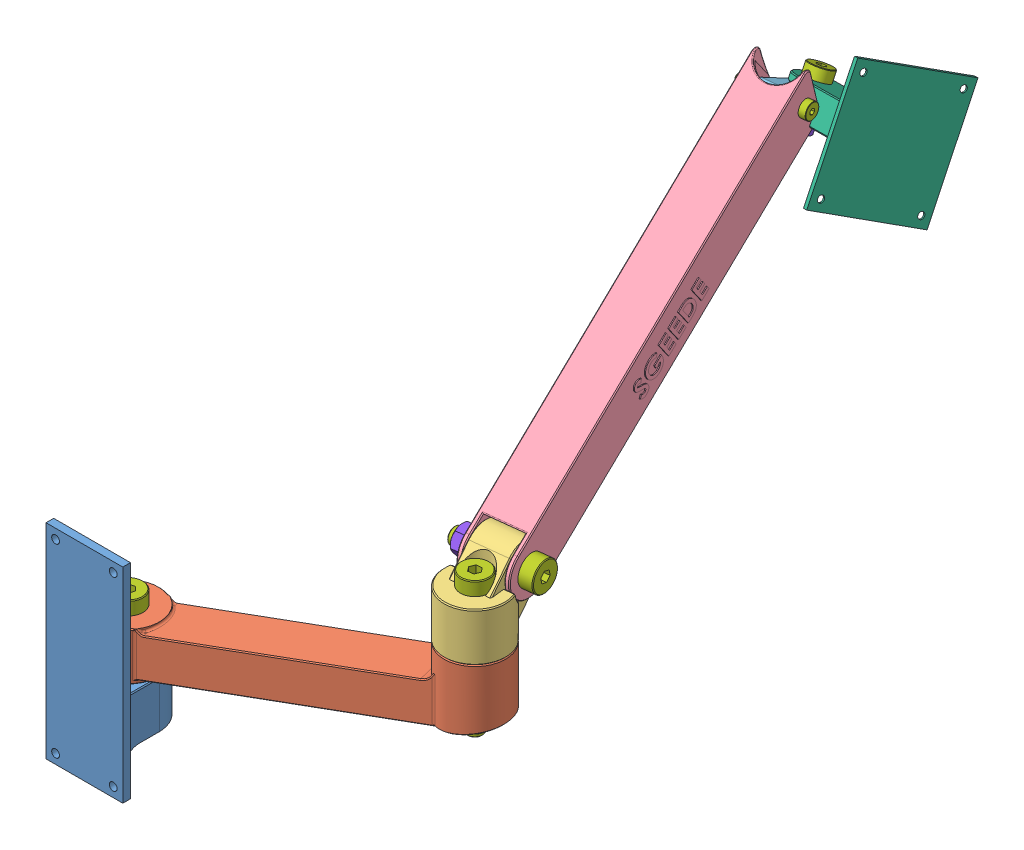
SolidWorks assembly lxhdstswall, configuration Default. Lengths in mm.
Overall size (397.37 577.27 596.46).
16 component instances, 8 part files, 31 mates.
Components (placement in the parent):
- WallBracket-1: WallBracket [Default] at (55.0507 127.7439 194.1309) size (80 213 78)
- Arm1-1: Arm1 [Default] at (29.5401 107.7439 138.7864) x (0.969584 0 -0.244757) z (0.244757 0 0.969584) size (361.03 125 64.03)
- Joint1-1: Joint1 [Default] at (343.0173 232.7439 85.438) x (-0.114521 0 -0.993421) z (0.993421 0 -0.114521) size (91.45 80.35 64)
- Arm2-1: Arm2 [Default] at (320.4593 406.352 -110.2427) x (-0.092601 0.588372 -0.803271) z (0.993421 0 -0.114521) size (449.82 50 51)
- Joint2-1: Joint2 [Default] at (299.6064 504.5489 -291.1318) x (-0.098971 -0.503119 -0.858531) z (0.993421 0 -0.114521) size (69 15 40)
- VesaMount-1: VesaMount [Default] at (397.6532 517.7237 -294.6599) x (-0.188445 0.482226 0.855539) z (-0.980392 -0.143481 -0.135072) size (120 120 121)
- socket head shoulder screw2_am-1: socket head shoulder screw2_am [B18.3.3M - 20 x 100 SHSS --N] at (55.0507 171.7439 158.1309) x (0 -1 0) z (0.270714 0 0.96266) size (136.4 30 30)
- socket head shoulder screw2_am-2: socket head shoulder screw2_am [B18.3.3M - 20 x 110 SHSS --N] at (343.0173 296.7439 85.438) x (0 -1 0) z (-0.796104 0 0.605159) size (146.4 30 30)
- socket head shoulder screw2_am-3: socket head shoulder screw2_am [B18.3.3M - 20 x 50 SHSS --N] at (377.8155 288.0892 46.7484) x (-0.993421 0 0.114521) z (0.034165 -0.954464 0.296365) size (86.4 30 30)
- socket head shoulder screw2_am-4: socket head shoulder screw2_am [B18.3.3M - 16 x 30 SHSS --N] at (297.1356 525.7018 -321.2972) x (0.057618 -0.864217 0.499809) z (0.929361 0.229293 0.289333) size (59.4 24 24)
- socket head shoulder screw2_am-5: socket head shoulder screw2_am [B18.3.3M - 10 x 50 SHSS --N] at (333.636 524.6147 -275.3648) x (-0.993421 0 0.114521) z (-0.114516 0.009842 -0.993373) size (70.25 16 16)
- hex flange nut_am-2: hex flange nut_am [B18.2.2.4M - Hex flange nut, M16 x 2 --N] at (55.0507 41.7439 158.1309) x (1 0 0) z (0 -1 0) size (34.5 34.5 16)
- hex flange nut_am-3: hex flange nut_am [B18.2.2.4M - Hex flange nut, M16 x 2 --N] at (343.0173 156.7439 85.438) x (0.998761 0 0.049755) z (0 -1 0) size (34.5 34.5 16)
- hex flange nut_am-4: hex flange nut_am [B18.2.2.4M - Hex flange nut, M16 x 2 --N] at (298.3418 288.0892 55.9101) x (0.009776 0.99635 0.084804) z (-0.993421 0 0.114521) size (34.5 34.5 16)
- hex flange nut_am-5: hex flange nut_am [B18.2.2.4M - Hex flange nut, M12 x 1.75 --N] at (300.1893 479.8983 -294.8073) x (-0.572702 -0.438686 -0.692508) z (0.057618 -0.864217 0.499809) size (26 26 12)
- hex flange nut_am-6: hex flange nut_am [B18.2.2.4M - Hex flange nut, M8 x 1.25 --N] at (269.0636 524.6147 -267.9209) x (0.11439 -0.047884 0.992281) z (-0.993421 0 0.114521) size (17.9 17.9 8)
Mates (geometry in assembly coordinates):
- Coincident1: coincident anti-aligned: plane of WallBracket-1 through (55.0507 107.7439 158.1309) normal (0 1 0); plane of Arm1-1 through (41.778 107.7439 187.2656) normal (0 -1 0)
- Concentric1: concentric aligned: cylinder of WallBracket-1 through (55.0507 21.2439 158.1309) axis (0 1 0) radius 10; cylinder of Arm1-1 through (55.0507 107.7439 158.1309) axis (0 1 0) radius 10
- Coincident2: coincident anti-aligned: plane of Arm1-1 through (368.5279 232.7439 104.7824) normal (0 1 0); plane of Joint1-1 through (343.0173 232.7439 85.438) normal (0 -1 0)
- Concentric2: concentric anti-aligned: cylinder of Arm1-1 through (343.0173 107.7439 85.438) axis (0 1 0) radius 10; cylinder of Joint1-1 through (343.0173 313.0892 85.438) axis (0 -1 0) radius 10
- Coincident3: coincident anti-aligned: plane of Joint1-1 through (358.9405 288.0892 48.9243) normal (0.993421 0 -0.114521); plane of Arm2-1 through (358.9405 288.0892 48.9243) normal (-0.993421 0 0.114521)
- Concentric3: concentric aligned: cylinder of Joint1-1 through (307.2826 288.0892 54.8794) axis (0.993421 0 -0.114521) radius 10; cylinder of Arm2-1 through (314.2365 288.0892 54.0777) axis (0.993421 0 -0.114521) radius 10
- Concentric4: concentric aligned: cylinder of Arm2-1 through (277.011 524.6147 -268.837) axis (0.993421 0 -0.114521) radius 5; cylinder of Joint2-1 through (281.9781 524.6147 -269.4096) axis (0.993421 0 -0.114521) radius 5
- Coincident4: coincident anti-aligned: plane of Arm2-1 through (318.2541 521.8701 -304.0119) normal (-0.993421 0 0.114521); plane of Joint2-1 through (317.0765 509.7138 -314.2266) normal (0.993421 0 -0.114521)
- LimitAngle2: limit planar angle = 0.247269 rad anti-aligned: plane of WallBracket-1 through (55.0507 127.7439 194.1309) normal (0 0 -1); plane of Arm1-1 through (84.4397 108.4612 176.4963) normal (0.244757 0 0.969584)
- Concentric5: concentric aligned: cylinder of Joint2-1 through (299.0658 496.7505 -304.5536) axis (-0.057618 0.864217 -0.499809) radius 8; cylinder of VesaMount-1 through (302.0907 451.3791 -278.3136) axis (-0.057618 0.864217 -0.499809) radius 8
- Coincident5: coincident anti-aligned: plane of Joint2-1 through (296.2147 509.7138 -311.8217) normal (-0.057618 0.864217 -0.499809); plane of VesaMount-1 through (298.2015 509.7138 -312.0507) normal (0.057618 -0.864217 0.499809)
- Concentric6: concentric aligned: cylinder of Arm1-1 through (55.0507 107.7439 158.1309) axis (0 1 0) radius 10; cylinder of socket head shoulder screw2_am-1 through (55.0507 178.0939 158.1309) axis (0 1 0) radius 9.99
- Concentric7: concentric aligned: cylinder of Joint1-1 through (307.2826 288.0892 54.8794) axis (0.993421 0 -0.114521) radius 10; cylinder of socket head shoulder screw2_am-3 through (384.1237 288.0892 46.0212) axis (0.993421 0 -0.114521) radius 9.99
- Coincident7: coincident anti-aligned: plane of Arm1-1 through (80.5613 157.7439 177.4753) normal (0 1 0); plane of socket head shoulder screw2_am-1 through (69.4906 157.7439 154.0701) normal (0 -1 0)
- Concentric8: concentric anti-aligned: cylinder of Joint1-1 through (343.0173 313.0892 85.438) axis (0 -1 0) radius 10; cylinder of socket head shoulder screw2_am-2 through (343.0173 303.0939 85.438) axis (0 1 0) radius 9.99
- Coincident8: coincident anti-aligned: plane of Joint1-1 through (343.0173 282.7439 85.438) normal (0 1 0); plane of socket head shoulder screw2_am-2 through (352.0947 282.7439 97.3795) normal (0 -1 0)
- Coincident9: coincident anti-aligned: plane of Arm2-1 through (345.2948 406.352 -113.1057) normal (0.993421 0 -0.114521); plane of socket head shoulder screw2_am-3 through (362.268 283.6143 34.1289) normal (-0.993421 0 0.114521)
- Concentric9: concentric aligned: cylinder of VesaMount-1 through (302.0907 451.3791 -278.3136) axis (-0.057618 0.864217 -0.499809) radius 8; cylinder of socket head shoulder screw2_am-4 through (296.7697 531.1896 -324.471) axis (-0.057618 0.864217 -0.499809) radius 7.992
- Coincident10: coincident anti-aligned: plane of VesaMount-1 through (388.1181 539.6141 -285.7216) normal (-0.057618 0.864217 -0.499809); plane of socket head shoulder screw2_am-4 through (302.1452 510.8214 -325.5959) normal (0.057618 -0.864217 0.499809)
- Concentric10: concentric aligned: cylinder of Joint2-1 through (281.9781 524.6147 -269.4096) axis (0.993421 0 -0.114521) radius 5; cylinder of socket head shoulder screw2_am-5 through (339.9442 524.6147 -276.092) axis (0.993421 0 -0.114521) radius 4.9935
- Coincident13: coincident anti-aligned: plane of Arm2-1 through (345.2948 406.352 -113.1057) normal (0.993421 0 -0.114521); plane of socket head shoulder screw2_am-5 through (326.691 532.6143 -274.4849) normal (-0.993421 0 0.114521)
- Concentric11: concentric anti-aligned: cylinder of socket head shoulder screw2_am-1 through (55.0507 178.0939 158.1309) axis (0 1 0) radius 9.99; cylinder of hex flange nut_am-2 through (55.0507 66.7814 158.1309) axis (0 -1 0) radius 8
- Coincident14: coincident anti-aligned: plane of WallBracket-1 through (55.0507 57.7439 158.1309) normal (0 -1 0); plane of hex flange nut_am-2 through (55.0507 57.7439 171.9873) normal (0 1 0)
- Concentric12: concentric anti-aligned: cylinder of socket head shoulder screw2_am-2 through (343.0173 303.0939 85.438) axis (0 1 0) radius 9.99; cylinder of hex flange nut_am-3 through (343.0173 181.7814 85.438) axis (0 -1 0) radius 8
- Coincident15: coincident anti-aligned: plane of Arm1-1 through (343.0173 172.7439 85.438) normal (0 -1 0); plane of hex flange nut_am-3 through (342.3279 172.7439 99.2772) normal (0 1 0)
- Concentric13: concentric anti-aligned: cylinder of socket head shoulder screw2_am-3 through (384.1237 288.0892 46.0212) axis (0.993421 0 -0.114521) radius 9.99; cylinder of hex flange nut_am-4 through (323.2146 288.0892 53.0428) axis (-0.993421 0 0.114521) radius 8
- Coincident16: coincident anti-aligned: plane of Arm2-1 through (295.6238 406.352 -107.3796) normal (-0.993421 0 0.114521); plane of hex flange nut_am-4 through (312.6555 289.2721 40.3627) normal (0.993421 0 -0.114521)
- Concentric14: concentric anti-aligned: cylinder of socket head shoulder screw2_am-4 through (296.7697 531.1896 -324.471) axis (-0.057618 0.864217 -0.499809) radius 7.992; cylinder of hex flange nut_am-5 through (298.7467 501.5361 -307.3213) axis (0.057618 -0.864217 0.499809) radius 6
- Coincident17: coincident anti-aligned: plane of VesaMount-1 through (389.8467 513.6876 -270.7273) normal (0.057618 -0.864217 0.499809); plane of hex flange nut_am-5 through (309.8065 498.1652 -288.3399) normal (-0.057618 0.864217 -0.499809)
- Concentric15: concentric anti-aligned: cylinder of socket head shoulder screw2_am-5 through (339.9442 524.6147 -276.092) axis (0.993421 0 -0.114521) radius 4.9935; cylinder of hex flange nut_am-6 through (293.9364 524.6147 -270.7882) axis (-0.993421 0 0.114521) radius 4
- Coincident18: coincident anti-aligned: plane of Arm2-1 through (295.6238 406.352 -107.3796) normal (-0.993421 0 0.114521); plane of hex flange nut_am-6 through (277.0521 532.1117 -268.48) normal (0.993421 0 -0.114521)
